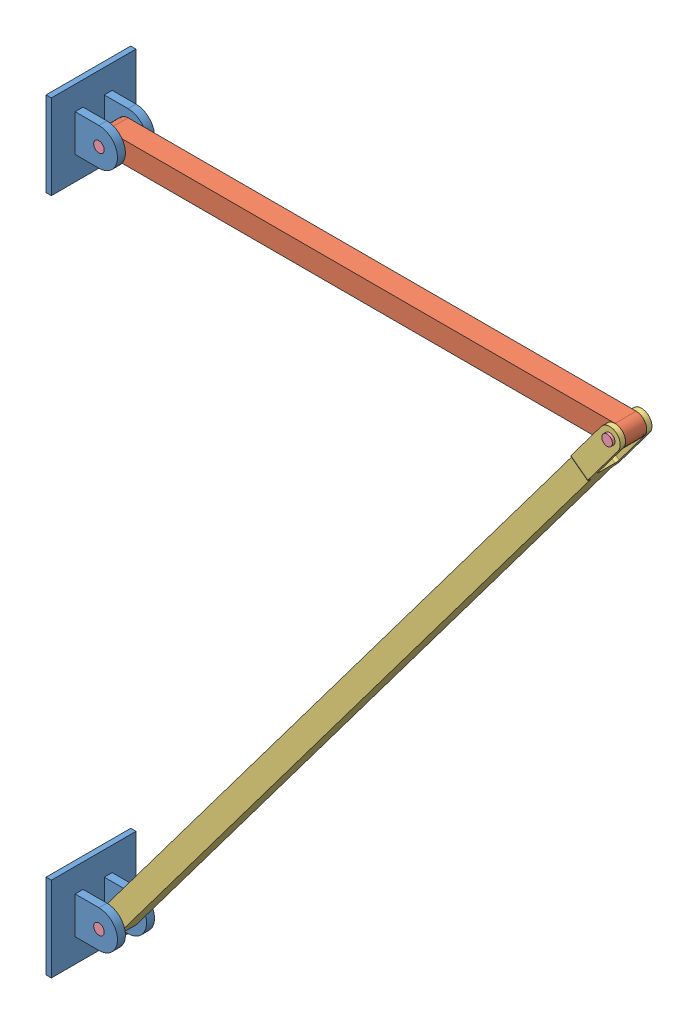
SolidWorks assembly Two Member Truss, configuration Default. Lengths in mm.
Overall size (662.31 914.4 101.6).
7 component instances, 4 part files, 14 mates.
Components (placement in the parent):
- Mount-2: Mount [Default] at origin size (57.15 101.6 101.6)
- Member 1-1: Member 1 [Default] at (339.725 0 0) size (635 25.4 25.4)
- Member 2-1: Member 2 [Default] at (339.725 -406.4 0) x (0.6 0.8 0) z (0 0 1) size (1041.4 25.4 38.1)
- Mount-3: Mount [Default] at (0 -812.8 0) size (57.15 101.6 101.6)
- Pin-1: Pin [Default] at (644.525 0 0) x (0 0 -1) z (1 0 0) size (44.45 12.7 12.7)
- Pin-2: Pin [Default] at (34.925 -812.8 0) x (0 0 1) z (-1 0 0) size (44.45 12.7 12.7)
- Pin-3: Pin [Default] at (34.925 0 0) x (0 0 1) z (-1 0 0) size (44.45 12.7 12.7)
Mates (geometry in assembly coordinates):
- Coincident1: coincident aligned: plane of Mount-2 through (0 0 0) normal (0 0 1); plane of Member 1-1 through (339.725 0 0) normal (0 0 1)
- Concentric3: concentric aligned: cylinder of Member 1-1 through (644.525 0 -12.7) axis (0 0 1) radius 6.35; cylinder of Member 2-1 through (644.525 0 -19.05) axis (0 0 1) radius 6.35
- Coincident2: coincident aligned: plane of Member 1-1 through (339.725 0 0) normal (0 0 1); plane of Member 2-1 through (339.725 -406.4 0) normal (0 0 1)
- Coincident3: coincident aligned: plane of Mount-2 through (0 0 0) normal (-1 0 0); plane of Mount-3 through (0 -812.8 0) normal (-1 0 0)
- Coincident4: coincident aligned: plane of Mount-2 through (0 0 0) normal (0 0 1); plane of Mount-3 through (0 -812.8 0) normal (0 0 1)
- Concentric4: concentric anti-aligned: cylinder of Mount-2 through (34.925 0 50.8) axis (0 0 -1) radius 6.35; cylinder of Member 1-1 through (34.925 0 -12.7) axis (0 0 1) radius 6.35
- Coincident5: coincident aligned: plane of Mount-2 through (0 0 0) normal (0 1 0); plane of Member 1-1 through (339.725 0 0) normal (0 1 0)
- Concentric5: concentric anti-aligned: cylinder of Member 2-1 through (34.925 -812.8 -12.7) axis (0 0 1) radius 6.35; cylinder of Mount-3 through (34.925 -812.8 50.8) axis (0 0 -1) radius 6.35
- Coincident6: coincident anti-aligned: plane of Member 2-1 through (339.725 -406.4 0) normal (0 0 1); plane of Pin-1 through (644.525 0 0) normal (0 0 -1)
- Concentric6: concentric aligned: cylinder of Member 1-1 through (644.525 0 -12.7) axis (0 0 1) radius 6.35; cylinder of Pin-1 through (644.525 0 -22.225) axis (0 0 1) radius 6.35
- Concentric7: concentric anti-aligned: cylinder of Member 2-1 through (34.925 -812.8 -12.7) axis (0 0 1) radius 6.35; cylinder of Pin-2 through (34.925 -812.8 22.225) axis (0 0 -1) radius 6.35
- Coincident7: coincident aligned: plane of Mount-3 through (0 -812.8 0) normal (0 0 1); plane of Pin-2 through (34.925 -812.8 0) normal (0 0 1)
- Concentric8: concentric anti-aligned: cylinder of Member 1-1 through (34.925 0 -12.7) axis (0 0 1) radius 6.35; cylinder of Pin-3 through (34.925 0 22.225) axis (0 0 -1) radius 6.35
- Coincident8: coincident aligned: plane of Member 1-1 through (339.725 0 0) normal (0 0 1); plane of Pin-3 through (34.925 0 0) normal (0 0 1)
